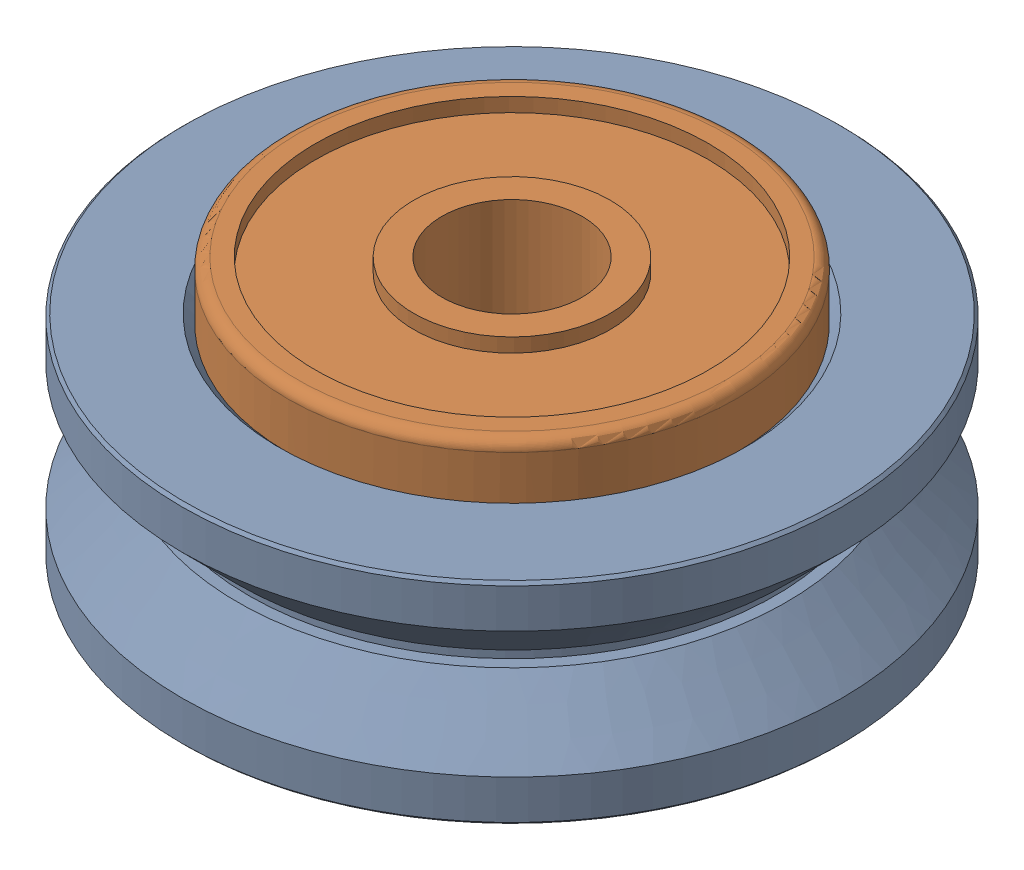
SolidWorks assembly B30037_ASM, configuration Default. Lengths in mm.
Overall size (23.5 11 23.5).
4 component instances, 3 part files, 0 mates.
Components (placement in the parent):
- B17021-1: B17021 [Default] at origin size (23.5 7.5 23.5)
- BEARING_5_16_5-1: BEARING_5_16_5 [Default] at (0 3 0) x (-1 0 0) z (0 0 1) size (16 5 16)
- BEARING_5_16_5-2: BEARING_5_16_5 [Default] at (0 -3 0) x (-1 0 0) z (0 0 1) size (16 5 16)
- B18026-1: B18026 [Default] at (0 -0.5 0) size (10 1 10)
